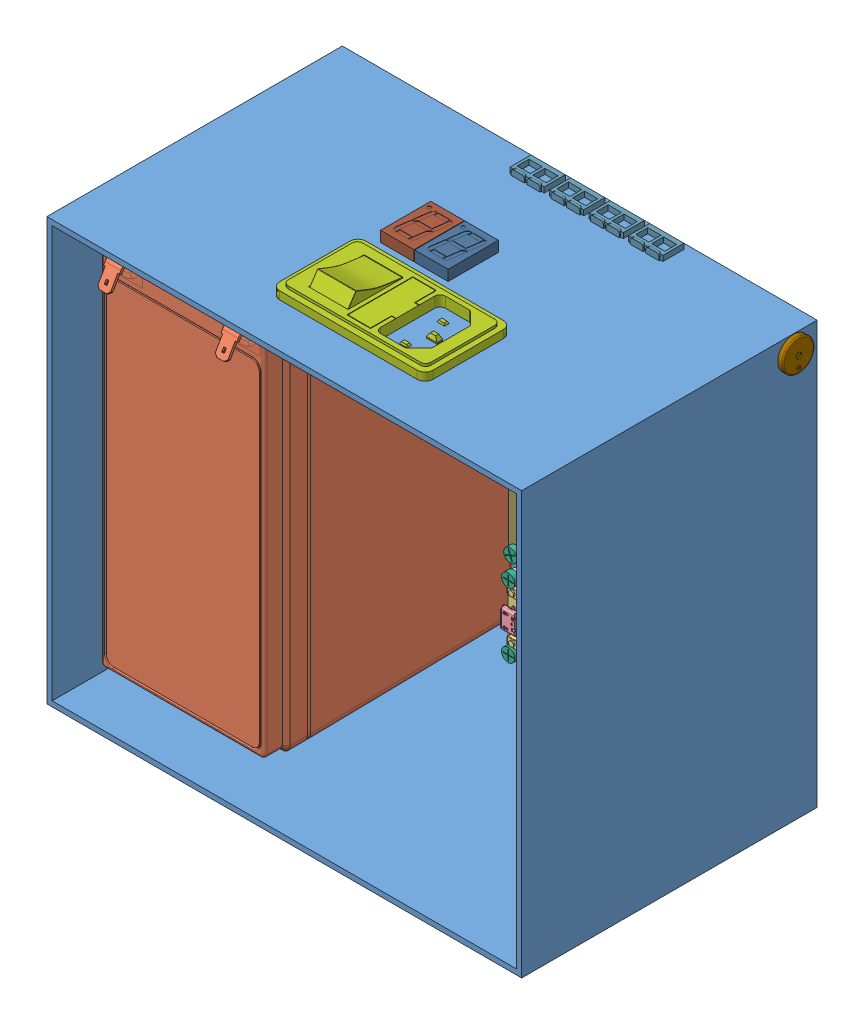
SolidWorks assembly Assem18, configuration Default. Lengths in mm.
Overall size (182 168.37 112).
160 component instances, 30 part files, 67 mates.
Components (placement in the parent):
- box-1: box [Default] at (65.7964 80.631 120.5562) size (180 160 112)
- Bateria UP7S-12-1: Bateria UP7S-12 [Default] at (20.8056 80.882 122.0562) size (65.34 151.34 102)
- ESP-32_v1-1: ESP-32_v1 [Predeterminado] at (91.454 11.5129 77.7562) x (0 -1 0) z (0 0 1) size (28.5 50.97 12.44)
  - 6.ESP-32-1: 6.ESP-32 [Predeterminado] at (-6.3746 -6.0494 52.8) x (1 0 0) z (0 -1 0) size (28.5 11.4 50.5)
  - micro_usb_47346-0001-1: micro_usb_47346-0001 [Default] at (-5.2796 -28.9494 55.525) x (1 0 0) z (0 -1 0) size (7.98 2.94 5.43)
  - KiCAD-ESP-WROOM-32_Predeterminado-1: KiCAD-ESP-WROOM-32_Predeterminado [Default] at (-5.2778 5.8273 53.7264) size (18.07 25.54 3.04)
- bolt-1: bolt [Default] at (108.6546 5.6375 131.3332) x (1 0 0) z (0 -1 0) size (5 11.5 5)
- bolt-3: bolt [Default] at (62.1546 30.1375 131.3332) x (1 0 0) z (0 -1 0) size (5 11.5 5)
- bolt-4: bolt [Default] at (108.6546 30.1375 131.3332) x (1 0 0) z (0 -1 0) size (5 11.5 5)
- bolt-5: bolt [Default] at (62.1546 5.6375 131.3332) x (1 0 0) z (0 -1 0) size (5 11.5 5)
- AC Power Inlet-1: AC Power Inlet [Default] at (59.3149 160.631 212.9715) size (58.1 34.87 32.67)
- HX-3S-D01-1: HX-3S-D01 [Default] at (144.695 116.9282 131.0562) x (0 -1 0) z (-1 0 0) size (51 3.71 22)
- bolt-6: bolt [Default] at (145.195 94.4282 131.3332) x (-0.923728 -0.383049 0) z (-0.383049 0.923728 0) size (5 11.5 5)
- bolt-7: bolt [Default] at (135.195 124.9282 131.3332) x (-0.923728 -0.383049 0) z (-0.383049 0.923728 0) size (5 11.5 5)
- bolt-8: bolt [Default] at (154.195 133.4282 131.3332) x (-0.923728 -0.383049 0) z (-0.383049 0.923728 0) size (5 11.5 5)
- buzzer-1: buzzer [Default] at (158.2964 154.4373 129.4815) x (0 0 1) z (1 0 0) size (13.85 12.39 15)
- Relay Module 2-1: Relay Module 2 [Default] at (159.3384 83.4662 130.5532) x (-1 0 0) z (0 0 1) size (46.64 42.63 21.17)
- single_relay-1: single_relay [Default] at (140.2854 20.8855 130.4562) x (0 1 0) z (1 0 0) size (26.3 17.6 39)
- bolt-9: bolt [Default] at (154.1354 10.5355 131.3332) x (-0.923728 -0.383049 0) z (-0.383049 0.923728 0) size (5 11.5 5)
- bolt-10: bolt [Default] at (126.4354 10.5355 131.3332) x (-0.923728 -0.383049 0) z (-0.383049 0.923728 0) size (5 11.5 5)
- bolt-11: bolt [Default] at (126.4354 31.2355 131.3332) x (0.508257 0.861205 0) z (0.861205 -0.508257 0) size (5 11.5 5)
- bolt-12: bolt [Default] at (154.1354 31.2355 131.3332) x (-0.923728 -0.383049 0) z (-0.383049 0.923728 0) size (5 11.5 5)
- bolt-13: bolt [Default] at (156.465 81.0426 131.3332) x (-0.923728 -0.383049 0) z (-0.383049 0.923728 0) size (5 11.5 5)
- bolt-15: bolt [Default] at (156.9351 43.6075 131.3332) x (-0.923728 -0.383049 0) z (-0.383049 0.923728 0) size (5 11.5 5)
- bolt-17: bolt [Default] at (117.4431 81.0426 131.3332) x (-0.923728 -0.383049 0) z (-0.383049 0.923728 0) size (5 11.5 5)
- pcb1-1: pcb1 [Default] at (85.2711 75.8094 132.0562) x (-1 0 0) z (0 0 -1) size (50 50.48 1)
- bolt-18: bolt [Default] at (62.9755 83.5178 131.3332) x (-0.923728 -0.383049 0) z (-0.383049 0.923728 0) size (5 11.5 5)
- bolt-19: bolt [Default] at (107.4978 83.5178 131.3332) x (-0.923728 -0.383049 0) z (-0.383049 0.923728 0) size (5 11.5 5)
- bolt-20: bolt [Default] at (107.4978 38.7198 131.3332) x (-0.923728 -0.383049 0) z (-0.383049 0.923728 0) size (5 11.5 5)
- bolt-21: bolt [Default] at (62.9755 38.7198 131.3332) x (-0.923728 -0.383049 0) z (-0.383049 0.923728 0) size (5 11.5 5)
- pcb2-1: pcb2 [Default] at (93.7202 114.021 132.0562) x (0 1 0) z (0 0 -1) size (50 68 2)
- bolt-22: bolt [Default] at (125.3716 90.7352 131.3332) x (-0.923728 -0.383049 0) z (-0.383049 0.923728 0) size (5 11.5 5)
- bolt-23: bolt [Default] at (61.9965 91.3146 131.3332) x (-0.923728 -0.383049 0) z (-0.383049 0.923728 0) size (5 11.5 5)
- bolt-24: bolt [Default] at (125.3716 136.8722 131.3332) x (-0.923728 -0.383049 0) z (-0.383049 0.923728 0) size (5 11.5 5)
- bolt-25: bolt [Default] at (61.9965 136.8722 131.3332) x (-0.923728 -0.383049 0) z (-0.383049 0.923728 0) size (5 11.5 5)
- Wago serie 221-5: Wago serie 221 [1] at (59.3267 144.631 122.5562) x (0 1 0) z (1 0 0) size (18.28 8.5 13)
- Wago serie 221-9: Wago serie 221 [1] at (74.3267 144.631 122.5562) x (0 1 0) z (1 0 0) size (18.28 8.5 13)
- Wago serie 221-10: Wago serie 221 [1] at (89.3267 144.631 122.5562) x (0 1 0) z (1 0 0) size (18.28 8.5 13)
- Wago serie 221-11: Wago serie 221 [1] at (104.3267 144.631 122.5562) x (0 1 0) z (1 0 0) size (18.28 8.5 13)
- mikroBUS_7_Seg_Click_Board-2: mikroBUS_7_Seg_Click_Board [Default] at (321.2452 87.8756 277.8889) x (0 0 1) z (0 1 0) size (41 25.8 17.94)
  - 7_Seg_Click_Board-1: 7_Seg_Click_Board [Default] at (-186.4371 -161.9019 60.2454) x (0 -1 0) z (0 0 1) size (25.8 41 17.94)
    - m20-9770842_asm.stp.1-1: m20-9770842_asm.stp.1 [Default] at (77.5496 46.3595 4.37) x (0 1 0) z (-1 0 0) size (20.32 11.48 2.54)
      - M20-977_ASM-1: M20-977_ASM [Default] at origin size (20.32 11.48 2.54)
        - M20-977-MOULD_2-1: M20-977-MOULD_2 [Default] at origin size (20.32 2.54 2.54)
        - M20-977-PIN.7-1: M20-977-PIN.7 [Default] at (2.54 -5.68 0) x (1 0 0) z (0 0 -1) size (0.64 11.48 0.64)
        - M20-977-PIN.7-2: M20-977-PIN.7 [Default] at (5.08 -5.68 0) x (1 0 0) z (0 0 -1) size (0.64 11.48 0.64)
        - M20-977-PIN.7-3: M20-977-PIN.7 [Default] at (7.62 -5.68 0) x (1 0 0) z (0 0 -1) size (0.64 11.48 0.64)
        - M20-977-PIN.7-4: M20-977-PIN.7 [Default] at (10.16 -5.68 0) x (1 0 0) z (0 0 -1) size (0.64 11.48 0.64)
        - M20-977-PIN.7-5: M20-977-PIN.7 [Default] at (12.7 -5.68 0) x (1 0 0) z (0 0 -1) size (0.64 11.48 0.64)
        - M20-977-PIN.7-6: M20-977-PIN.7 [Default] at (15.24 -5.68 0) x (1 0 0) z (0 0 -1) size (0.64 11.48 0.64)
        - M20-977-PIN.7-7: M20-977-PIN.7 [Default] at (17.78 -5.68 0) x (1 0 0) z (0 0 -1) size (0.64 11.48 0.64)
        - M20-977-PIN.7-8: M20-977-PIN.7 [Default] at (20.32 -5.68 0) x (1 0 0) z (0 0 -1) size (0.64 11.48 0.64)
    - m20-9770842_asm.stp-1: m20-9770842_asm.stp [Default] at (100.4096 46.3595 4.37) x (0 1 0) z (-1 0 0) size (20.32 11.48 2.54)
      - M20-977_ASM_2-1: M20-977_ASM_2 [Default] at origin size (20.32 11.48 2.54)
        - M20-977-MOULD-1: M20-977-MOULD [Default] at origin size (20.32 2.54 2.54)
        - M20-977-PIN.5-1: M20-977-PIN.5 [Default] at (2.54 -5.68 0) x (1 0 0) z (0 0 -1) size (0.64 11.48 0.64)
        - M20-977-PIN.5-2: M20-977-PIN.5 [Default] at (5.08 -5.68 0) x (1 0 0) z (0 0 -1) size (0.64 11.48 0.64)
        - M20-977-PIN.5-3: M20-977-PIN.5 [Default] at (7.62 -5.68 0) x (1 0 0) z (0 0 -1) size (0.64 11.48 0.64)
        - M20-977-PIN.5-4: M20-977-PIN.5 [Default] at (10.16 -5.68 0) x (1 0 0) z (0 0 -1) size (0.64 11.48 0.64)
        - M20-977-PIN.5-5: M20-977-PIN.5 [Default] at (12.7 -5.68 0) x (1 0 0) z (0 0 -1) size (0.64 11.48 0.64)
        - M20-977-PIN.5-6: M20-977-PIN.5 [Default] at (15.24 -5.68 0) x (1 0 0) z (0 0 -1) size (0.64 11.48 0.64)
        - M20-977-PIN.5-7: M20-977-PIN.5 [Default] at (17.78 -5.68 0) x (1 0 0) z (0 0 -1) size (0.64 11.48 0.64)
        - M20-977-PIN.5-8: M20-977-PIN.5 [Default] at (20.32 -5.68 0) x (1 0 0) z (0 0 -1) size (0.64 11.48 0.64)
    - arduino_uno_MLC0603.1.1.8-1: arduino_uno_MLC0603.1.1.8 [Default] at (93.2677 51.543 8.51) x (1 0 0) z (0 -1 0) size (2.36 0.6 1.03)
      - p4-1: p4 [Default] at origin size (1.55 0.45 0.8)
      - p3-1: p3 [Default] at origin size (1 0.03 0.8)
      - p2-1: p2 [Default] at origin size (0.8 0.6 1.03)
      - p1-1: p1 [Default] at origin size (0.8 0.6 1.03)
    - User_Library-arduino_uno_ssot3.1.1-1: User_Library-arduino_uno_ssot3.1.1 [Default] at (84.6189 60.8527 8.41) x (0 1 0) z (1 0 0) size (3 1.13 3.09)
    - Everlight_67-21SRC-TR8.STEP-1: Everlight_67-21SRC-TR8.STEP [Default] at (83.1478 51.2463 8.51) x (0 -1 0) z (-1 0 0) size (2.8 1.86 3.5)
      - User_Library-Everlight_67-21SRC-TR8-1: User_Library-Everlight_67-21SRC-TR8 [Default] at origin size (2.8 1.86 3.5)
        - User_Library-Everlight_67-21SRC-TR8_Imported_3-1: User_Library-Everlight_67-21SRC-TR8_Imported_3 [Default] at origin size (0.48 0.2 0.48)
        - User_Library-Everlight_67-21SRC-TR8_Imported_4-1: User_Library-Everlight_67-21SRC-TR8_Imported_4 [Default] at origin size (2.4 0.85 2.4)
        - User_Library-Everlight_67-21SRC-TR8_Imported-1: User_Library-Everlight_67-21SRC-TR8_Imported [Default] at origin size (2.2 1.01 3.5)
        - User_Library-Everlight_67-21SRC-TR8_Imported_2-1: User_Library-Everlight_67-21SRC-TR8_Imported_2 [Default] at origin size (2.8 1.8 3.2)
    - Disp_SA56-11.1-1: Disp_SA56-11.1 [Default] at (77.4495 69.2194 8.4773) size (12.7 19.05 12)
      - SW3dPS-Disp_SA56-11-1: SW3dPS-Disp_SA56-11 [Default] at origin size (12.7 19.05 12)
        - SW3dPS-Disp_SA56-11_Open_CASCADE_STEP_translator_6.2_78.2-1: SW3dPS-Disp_SA56-11_Open_CASCADE_STEP_translator_6.2_78.2 [Default] at origin size (12.7 19.05 12)
          - SW3dPS-Disp_SA56-11_Disp_SA56-12_2-1: SW3dPS-Disp_SA56-11_Disp_SA56-12_2 [Default] at (5.0801 7.6201 8.0327) x (1 0 0) z (0 -1 0) size (12.7 12 19.05)
    - Disp_SA56-11-1: Disp_SA56-11 [Default] at (90.3495 69.2194 8.4773) size (12.7 19.05 12)
      - SW3dPS-Disp_SA56-11_2-1: SW3dPS-Disp_SA56-11_2 [Default] at origin size (12.7 19.05 12)
        - SW3dPS-Disp_SA56-11_Open_CASCADE_STEP_translator_6.2_78.2_2-1: SW3dPS-Disp_SA56-11_Open_CASCADE_STEP_translator_6.2_78.2_2 [Default] at origin size (12.7 19.05 12)
          - SW3dPS-Disp_SA56-11_Disp_SA56-12-1: SW3dPS-Disp_SA56-11_Disp_SA56-12 [Default] at (5.0801 7.6201 8.0327) x (1 0 0) z (0 -1 0) size (12.7 12 19.05)
    - 7_Seg_Click_Board-1: 7_Seg_Click_Board [Default] at (0 0.5 0) size (25.8 41 1.6)
    - arduino_uno_MLC0603.1.1.8-2: arduino_uno_MLC0603.1.1.8 [Default] at (97.3056 65.7088 8.51) x (0 -1 0) z (-1 0 0) size (2.36 0.6 1.03)
      - p4-1: p4 [Default] at origin size (1.55 0.45 0.8)
      - p3-1: p3 [Default] at origin size (1 0.03 0.8)
      - p2-1: p2 [Default] at origin size (0.8 0.6 1.03)
      - p1-1: p1 [Default] at origin size (0.8 0.6 1.03)
    - arduino_uno_MLC0603.1.1.8-3: arduino_uno_MLC0603.1.1.8 [Default] at (97.3056 61.7088 8.51) x (0 -1 0) z (-1 0 0) size (2.36 0.6 1.03)
      - p4-1: p4 [Default] at origin size (1.55 0.45 0.8)
      - p3-1: p3 [Default] at origin size (1 0.03 0.8)
      - p2-1: p2 [Default] at origin size (0.8 0.6 1.03)
      - p1-1: p1 [Default] at origin size (0.8 0.6 1.03)
    - arduino_uno_MLC0603.1.1.8-4: arduino_uno_MLC0603.1.1.8 [Default] at (95.0056 65.7088 8.51) x (0 -1 0) z (-1 0 0) size (2.36 0.6 1.03)
      - p4-1: p4 [Default] at origin size (1.55 0.45 0.8)
      - p3-1: p3 [Default] at origin size (1 0.03 0.8)
      - p2-1: p2 [Default] at origin size (0.8 0.6 1.03)
      - p1-1: p1 [Default] at origin size (0.8 0.6 1.03)
    - arduino_uno_MLC0603.1.1.8-5: arduino_uno_MLC0603.1.1.8 [Default] at (92.7056 65.7088 8.51) x (0 -1 0) z (-1 0 0) size (2.36 0.6 1.03)
      - p4-1: p4 [Default] at origin size (1.55 0.45 0.8)
      - p3-1: p3 [Default] at origin size (1 0.03 0.8)
      - p2-1: p2 [Default] at origin size (0.8 0.6 1.03)
      - p1-1: p1 [Default] at origin size (0.8 0.6 1.03)
    - arduino_uno_MLC0603.1.1.8-6: arduino_uno_MLC0603.1.1.8 [Default] at (90.4056 65.7088 8.51) x (0 -1 0) z (-1 0 0) size (2.36 0.6 1.03)
      - p4-1: p4 [Default] at origin size (1.55 0.45 0.8)
      - p3-1: p3 [Default] at origin size (1 0.03 0.8)
      - p2-1: p2 [Default] at origin size (0.8 0.6 1.03)
      - p1-1: p1 [Default] at origin size (0.8 0.6 1.03)
    - arduino_uno_MLC0603.1.1.8-7: arduino_uno_MLC0603.1.1.8 [Default] at (90.4056 61.7088 8.51) x (0 -1 0) z (-1 0 0) size (2.36 0.6 1.03)
      - p4-1: p4 [Default] at origin size (1.55 0.45 0.8)
      - p3-1: p3 [Default] at origin size (1 0.03 0.8)
      - p2-1: p2 [Default] at origin size (0.8 0.6 1.03)
      - p1-1: p1 [Default] at origin size (0.8 0.6 1.03)
    - arduino_uno_MLC0603.1.1.8-8: arduino_uno_MLC0603.1.1.8 [Default] at (88.1056 65.7088 8.51) x (0 -1 0) z (-1 0 0) size (2.36 0.6 1.03)
      - p4-1: p4 [Default] at origin size (1.55 0.45 0.8)
      - p3-1: p3 [Default] at origin size (1 0.03 0.8)
      - p2-1: p2 [Default] at origin size (0.8 0.6 1.03)
      - p1-1: p1 [Default] at origin size (0.8 0.6 1.03)
    - arduino_uno_MLC0603.1.1.8-9: arduino_uno_MLC0603.1.1.8 [Default] at (88.1056 61.7088 8.51) x (0 -1 0) z (-1 0 0) size (2.36 0.6 1.03)
      - p4-1: p4 [Default] at origin size (1.55 0.45 0.8)
      - p3-1: p3 [Default] at origin size (1 0.03 0.8)
      - p2-1: p2 [Default] at origin size (0.8 0.6 1.03)
      - p1-1: p1 [Default] at origin size (0.8 0.6 1.03)
    - arduino_uno_MLC0603.1.1.8-10: arduino_uno_MLC0603.1.1.8 [Default] at (85.8056 65.7088 8.51) x (0 -1 0) z (-1 0 0) size (2.36 0.6 1.03)
      - p4-1: p4 [Default] at origin size (1.55 0.45 0.8)
      - p3-1: p3 [Default] at origin size (1 0.03 0.8)
      - p2-1: p2 [Default] at origin size (0.8 0.6 1.03)
      - p1-1: p1 [Default] at origin size (0.8 0.6 1.03)
    - arduino_uno_MLC0603.1.1.8-11: arduino_uno_MLC0603.1.1.8 [Default] at (83.5056 65.7088 8.51) x (0 -1 0) z (-1 0 0) size (2.36 0.6 1.03)
      - p4-1: p4 [Default] at origin size (1.55 0.45 0.8)
      - p3-1: p3 [Default] at origin size (1 0.03 0.8)
      - p2-1: p2 [Default] at origin size (0.8 0.6 1.03)
      - p1-1: p1 [Default] at origin size (0.8 0.6 1.03)
    - arduino_uno_MLC0603.1.1.8-12: arduino_uno_MLC0603.1.1.8 [Default] at (81.2056 65.7088 8.51) x (0 -1 0) z (-1 0 0) size (2.36 0.6 1.03)
      - p4-1: p4 [Default] at origin size (1.55 0.45 0.8)
      - p3-1: p3 [Default] at origin size (1 0.03 0.8)
      - p2-1: p2 [Default] at origin size (0.8 0.6 1.03)
      - p1-1: p1 [Default] at origin size (0.8 0.6 1.03)
    - arduino_uno_MLC0603.1.1.8-13: arduino_uno_MLC0603.1.1.8 [Default] at (81.2056 61.7088 8.51) x (0 -1 0) z (-1 0 0) size (2.36 0.6 1.03)
      - p4-1: p4 [Default] at origin size (1.55 0.45 0.8)
      - p3-1: p3 [Default] at origin size (1 0.03 0.8)
      - p2-1: p2 [Default] at origin size (0.8 0.6 1.03)
      - p1-1: p1 [Default] at origin size (0.8 0.6 1.03)
    - arduino_uno_MLC0603.1.1.8-14: arduino_uno_MLC0603.1.1.8 [Default] at (89.3331 51.4771 8.51) x (0 -1 0) z (-1 0 0) size (2.36 0.6 1.03)
      - p4-1: p4 [Default] at origin size (1.55 0.45 0.8)
      - p3-1: p3 [Default] at origin size (1 0.03 0.8)
      - p2-1: p2 [Default] at origin size (0.8 0.6 1.03)
      - p1-1: p1 [Default] at origin size (0.8 0.6 1.03)
    - arduino_uno_MLC0603.1.1.8-15: arduino_uno_MLC0603.1.1.8 [Default] at (89.3331 56.4771 8.51) x (0 -1 0) z (-1 0 0) size (2.36 0.6 1.03)
      - p4-1: p4 [Default] at origin size (1.55 0.45 0.8)
      - p3-1: p3 [Default] at origin size (1 0.03 0.8)
      - p2-1: p2 [Default] at origin size (0.8 0.6 1.03)
      - p1-1: p1 [Default] at origin size (0.8 0.6 1.03)
    - arduino_uno_MLC0603.1.1.8-16: arduino_uno_MLC0603.1.1.8 [Default] at (87.0331 51.4771 8.51) x (0 -1 0) z (-1 0 0) size (2.36 0.6 1.03)
      - p4-1: p4 [Default] at origin size (1.55 0.45 0.8)
      - p3-1: p3 [Default] at origin size (1 0.03 0.8)
      - p2-1: p2 [Default] at origin size (0.8 0.6 1.03)
      - p1-1: p1 [Default] at origin size (0.8 0.6 1.03)
    - User_Library-arduino_uno_ssot3.1.1-2: User_Library-arduino_uno_ssot3.1.1 [Default] at (94.2189 60.8527 8.41) x (0 1 0) z (1 0 0) size (3 1.13 3.09)
Mates (geometry in assembly coordinates):
- Coincident1: coincident anti-aligned: plane of box-1 through (65.7964 80.631 122.5562) normal (0 0 1); plane of Bateria UP7S-12-1 through (20.8056 80.882 122.5562) normal (0 0 -1)
- Coincident5: coincident anti-aligned: plane of box-1 through (65.7964 80.631 122.5562) normal (0 0 1); plane of ESP-32_v1-1/6.ESP-32-1 through (85.4046 17.8875 122.5562) normal (0 0 -1)
- Concentric1: concentric anti-aligned: cylinder of ESP-32_v1-1/6.ESP-32-1 through (108.6546 5.6375 132.0562) axis (0 0 -1) radius 1.5; cylinder of bolt-1 through (108.6546 5.6375 137.84) axis (0 0 1) radius 1.5
- Coincident6: coincident aligned: plane of ESP-32_v1-1/6.ESP-32-1 through (85.4046 17.8875 132.0562) normal (0 0 1); circle of bolt-1
- Concentric2: concentric anti-aligned: cylinder of ESP-32_v1-1/6.ESP-32-1 through (108.6546 30.1375 132.0562) axis (0 0 -1) radius 1.5; cylinder of bolt-4 through (108.6546 30.1375 137.84) axis (0 0 1) radius 1.5
- Concentric3: concentric anti-aligned: cylinder of ESP-32_v1-1/6.ESP-32-1 through (62.1546 5.6375 132.0562) axis (0 0 -1) radius 1.5; cylinder of bolt-5 through (62.1546 5.6375 137.84) axis (0 0 1) radius 1.5
- Concentric4: concentric anti-aligned: cylinder of ESP-32_v1-1/6.ESP-32-1 through (62.1546 30.1375 132.0562) axis (0 0 -1) radius 1.5; cylinder of bolt-3 through (62.1546 30.1375 137.84) axis (0 0 1) radius 1.5
- Coincident7: coincident aligned: plane of ESP-32_v1-1/6.ESP-32-1 through (85.4046 17.8875 132.0562) normal (0 0 1); circle of bolt-3
- Coincident8: coincident aligned: plane of ESP-32_v1-1/6.ESP-32-1 through (85.4046 17.8875 132.0562) normal (0 0 1); circle of bolt-5
- Coincident9: coincident aligned: plane of ESP-32_v1-1/6.ESP-32-1 through (85.4046 17.8875 132.0562) normal (0 0 1); circle of bolt-4
- Coincident13: coincident anti-aligned: plane of box-1 through (145.7964 160.631 122.5562) normal (0 1 0); plane of AC Power Inlet-1 through (83.3649 160.631 199.4715) normal (0 -1 0)
- Concentric5: concentric aligned: cylinder of HX-3S-D01-1 through (145.195 94.4282 131.0462) axis (0 0 1) radius 0.6; cylinder of bolt-6 through (145.195 94.4282 137.84) axis (0 0 1) radius 1.5
- Coincident15: coincident anti-aligned: plane of HX-3S-D01-1 through (144.695 116.9282 132.0562) normal (0 0 1); plane of bolt-6 through (146.5805 95.0028 132.0562) normal (0 0 -1)
- Coincident16: coincident anti-aligned: plane of box-1 through (65.7964 80.631 122.5562) normal (0 0 1); plane of bolt-6 through (145.195 94.4282 122.5562) normal (0 0 -1)
- Concentric6: concentric aligned: cylinder of HX-3S-D01-1 through (154.195 133.4282 131.0462) axis (0 0 1) radius 0.6; cylinder of bolt-8 through (154.195 133.4282 137.84) axis (0 0 1) radius 1.5
- Coincident17: coincident aligned: plane of HX-3S-D01-1 through (144.695 116.9282 132.0562) normal (0 0 1); circle of bolt-8
- Concentric7: concentric anti-aligned: circle of HX-3S-D01-1; cylinder of bolt-7 through (135.195 124.9282 137.84) axis (0 0 1) radius 1.5
- Coincident18: coincident aligned: plane of HX-3S-D01-1 through (144.695 116.9282 132.0562) normal (0 0 1); circle of bolt-7
- Parallel5: parallel anti-aligned: plane of box-1 through (65.7964 80.631 122.5562) normal (0 0 1); plane of single_relay-1 through (140.2854 20.8855 130.4562) normal (0 0 -1)
- Concentric8: concentric anti-aligned: cylinder of single_relay-1 through (154.1354 31.2355 148.0562) axis (0 0 -1) radius 1.5; cylinder of bolt-12 through (154.1354 31.2355 137.84) axis (0 0 1) radius 1.5
- Concentric9: concentric anti-aligned: cylinder of single_relay-1 through (126.4354 31.2355 148.0562) axis (0 0 -1) radius 1.5; cylinder of bolt-11 through (126.4354 31.2355 137.84) axis (0 0 1) radius 1.5
- Coincident33: coincident aligned: circle of single_relay-1; cylinder of bolt-10 through (126.4354 10.5355 137.84) axis (0 0 1) radius 1.5
- Coincident34: coincident anti-aligned: circle of single_relay-1; cylinder of bolt-9 through (154.1354 10.5355 137.84) axis (0 0 1) radius 1.5
- Coincident35: coincident aligned: plane of single_relay-1 through (140.2854 20.8855 132.0562) normal (0 0 1); circle of bolt-11
- Coincident36: coincident aligned: plane of single_relay-1 through (140.2854 20.8855 132.0562) normal (0 0 1); circle of bolt-12
- Coincident37: coincident aligned: plane of single_relay-1 through (140.2854 20.8855 132.0562) normal (0 0 1); circle of bolt-9
- Coincident38: coincident aligned: plane of single_relay-1 through (140.2854 20.8855 132.0562) normal (0 0 1); circle of bolt-10
- Coincident39: coincident anti-aligned: plane of box-1 through (65.7964 80.631 122.5562) normal (0 0 1); plane of bolt-11 through (126.4354 31.2355 122.5562) normal (0 0 -1)
- Coincident40: coincident aligned: circle of Relay Module 2-1; cylinder of bolt-13 through (156.465 81.0426 137.84) axis (0 0 1) radius 1.5
- Coincident41: coincident aligned: circle of Relay Module 2-1; cylinder of bolt-15 through (156.9351 43.6075 137.84) axis (0 0 1) radius 1.5
- Coincident43: coincident aligned: plane of Relay Module 2-1 through (159.3384 83.4662 132.0562) normal (0 0 1); circle of bolt-15
- Coincident44: coincident aligned: plane of Relay Module 2-1 through (159.3384 83.4662 132.0562) normal (0 0 1); circle of bolt-13
- Coincident46: coincident anti-aligned: plane of box-1 through (65.7964 80.631 122.5562) normal (0 0 1); plane of bolt-12 through (154.1354 31.2355 122.5562) normal (0 0 -1)
- Coincident48: coincident anti-aligned: circle of Relay Module 2-1; cylinder of bolt-17 through (117.4431 81.0426 137.84) axis (0 0 1) radius 1.5
- Coincident49: coincident aligned: plane of Relay Module 2-1 through (159.3384 83.4662 132.0562) normal (0 0 1); circle of bolt-17
- Coincident50: coincident aligned: plane of box-1 through (65.7964 80.631 122.5562) normal (0 0 1); circle of bolt-13
- Concentric11: concentric aligned: cylinder of pcb1-1 through (62.9755 38.7198 131.0562) axis (0 0 1) radius 1.5; cylinder of bolt-21 through (62.9755 38.7198 137.84) axis (0 0 1) radius 1.5
- Concentric12: concentric aligned: circle of pcb1-1; circle of bolt-18
- Coincident52: coincident aligned: circle of pcb1-1; cylinder of bolt-20 through (107.4978 38.7198 137.84) axis (0 0 1) radius 1.5
- Concentric13: concentric aligned: cylinder of pcb1-1 through (107.4978 83.5178 131.0562) axis (0 0 1) radius 1.5; cylinder of bolt-19 through (107.4978 83.5178 137.84) axis (0 0 1) radius 1.5
- Coincident53: coincident aligned: plane of pcb1-1 through (85.2711 75.8094 132.0562) normal (0 0 1); circle of bolt-19
- Coincident54: coincident aligned: plane of pcb1-1 through (85.2711 75.8094 132.0562) normal (0 0 1); circle of bolt-20
- Coincident55: coincident aligned: plane of pcb1-1 through (85.2711 75.8094 132.0562) normal (0 0 1); circle of bolt-18
- Coincident56: coincident aligned: plane of pcb1-1 through (85.2711 75.8094 132.0562) normal (0 0 1); circle of bolt-21
- Coincident61: coincident anti-aligned: plane of box-1 through (65.7964 80.631 122.5562) normal (0 0 1); plane of bolt-19 through (107.4978 83.5178 122.5562) normal (0 0 -1)
- Parallel9: parallel: plane of box-1 through (145.7964 0.631 122.5562) normal (1 0 0); plane of pcb1-1 through (105.3515 116.5085 131.0562) normal (1 0 0)
- Parallel11: parallel aligned: plane of box-1 through (145.7964 0.631 122.5562) normal (0 -1 0); plane of ESP-32_v1-1/6.ESP-32-1 through (85.4046 3.6375 132.0562) normal (0 -1 0)
- Parallel12: parallel anti-aligned: plane of box-1 through (65.7964 80.631 122.5562) normal (0 0 1); plane of pcb2-1 through (93.7202 114.021 130.0562) normal (0 0 -1)
- Concentric14: concentric aligned: circle of pcb2-1; cylinder of bolt-22 through (125.3716 90.7352 137.84) axis (0 0 1) radius 2.5
- Concentric15: concentric aligned: circle of pcb2-1; circle of bolt-23
- Concentric16: concentric aligned: cylinder of pcb2-1 through (125.3716 136.8722 130.0562) axis (0 0 1) radius 1.5; circle of bolt-24
- Concentric17: concentric aligned: cylinder of pcb2-1 through (61.9965 136.8722 130.0562) axis (0 0 1) radius 1.5; circle of bolt-25
- Coincident66: coincident aligned: plane of pcb2-1 through (93.7202 114.021 132.0562) normal (0 0 1); circle of bolt-23
- Coincident67: coincident aligned: plane of pcb2-1 through (93.7202 114.021 132.0562) normal (0 0 1); circle of bolt-25
- Coincident68: coincident aligned: plane of pcb2-1 through (93.7202 114.021 132.0562) normal (0 0 1); circle of bolt-22
- Coincident69: coincident aligned: plane of pcb2-1 through (93.7202 114.021 132.0562) normal (0 0 1); circle of bolt-24
- Coincident72: coincident anti-aligned: plane of box-1 through (65.7964 80.631 122.5562) normal (0 0 1); plane of bolt-23 through (61.9965 91.3146 122.5562) normal (0 0 -1)
- Coincident73: coincident anti-aligned: plane of box-1 through (65.7964 80.631 122.5562) normal (0 0 1); plane of Wago serie 221-5 through (72.3267 144.631 122.5562) normal (0 0 -1)
- Distance11: distance = 2 mm aligned: plane of box-1 through (145.7964 160.631 122.5562) normal (0 1 0); plane of Wago serie 221-5 through (72.3267 162.631 122.5562) normal (0 1 0)
- Parallel15: parallel anti-aligned: plane of box-1 through (145.7964 160.631 122.5562) normal (0 1 0); plane of pcb2-1 through (127.7202 89.021 130.0562) normal (0 -1 0)
- Parallel16: parallel anti-aligned: plane of box-1 through (145.7964 160.631 122.5562) normal (0 1 0); plane of HX-3S-D01-1 through (155.695 91.4282 131.0462) normal (0 -1 0)
- Coincident78: coincident aligned: plane of AC Power Inlet-1 through (83.3649 164.631 199.4715) normal (0 1 0); plane of mikroBUS_7_Seg_Click_Board-2/7_Seg_Click_Board-1/Disp_SA56-11.1-1/SW3dPS-Disp_SA56-11-1/SW3dPS-Disp_SA56-11_Open_CASCADE_STEP_translator_6.2_78.2-1/SW3dPS-Disp_SA56-11_Disp_SA56-12_2-1 through (70.4637 164.631 177.8164) normal (0 1 0)
- Parallel17: parallel anti-aligned: plane of box-1 through (65.7964 80.631 122.5562) normal (0 0 1); plane of mikroBUS_7_Seg_Click_Board-2/7_Seg_Click_Board-1/Disp_SA56-11-1/SW3dPS-Disp_SA56-11_2-1/SW3dPS-Disp_SA56-11_Open_CASCADE_STEP_translator_6.2_78.2_2-1/SW3dPS-Disp_SA56-11_Disp_SA56-12-1 through (70.2637 156.631 158.7664) normal (0 0 -1)
- Coincident80: coincident anti-aligned: plane of box-1 through (65.7964 80.631 122.5562) normal (0 0 1); plane of buzzer-1 through (161.7964 160.631 122.5562) normal (0 0 -1)
- Coincident83: coincident aligned: plane of box-1 through (145.7964 160.631 122.5562) normal (0 1 0); plane of buzzer-1 through (161.7964 160.631 136.4068) normal (0 1 0)
- Parallel21: parallel aligned: plane of box-1 through (165.7964 80.631 120.5562) normal (1 0 0); plane of single_relay-1 through (156.9354 7.7355 132.0562) normal (1 0 0)
- Coincident87: coincident aligned: plane of box-1 through (165.7964 80.631 120.5562) normal (1 0 0); plane of buzzer-1 through (165.7964 154.4373 129.4815) normal (1 0 0)
